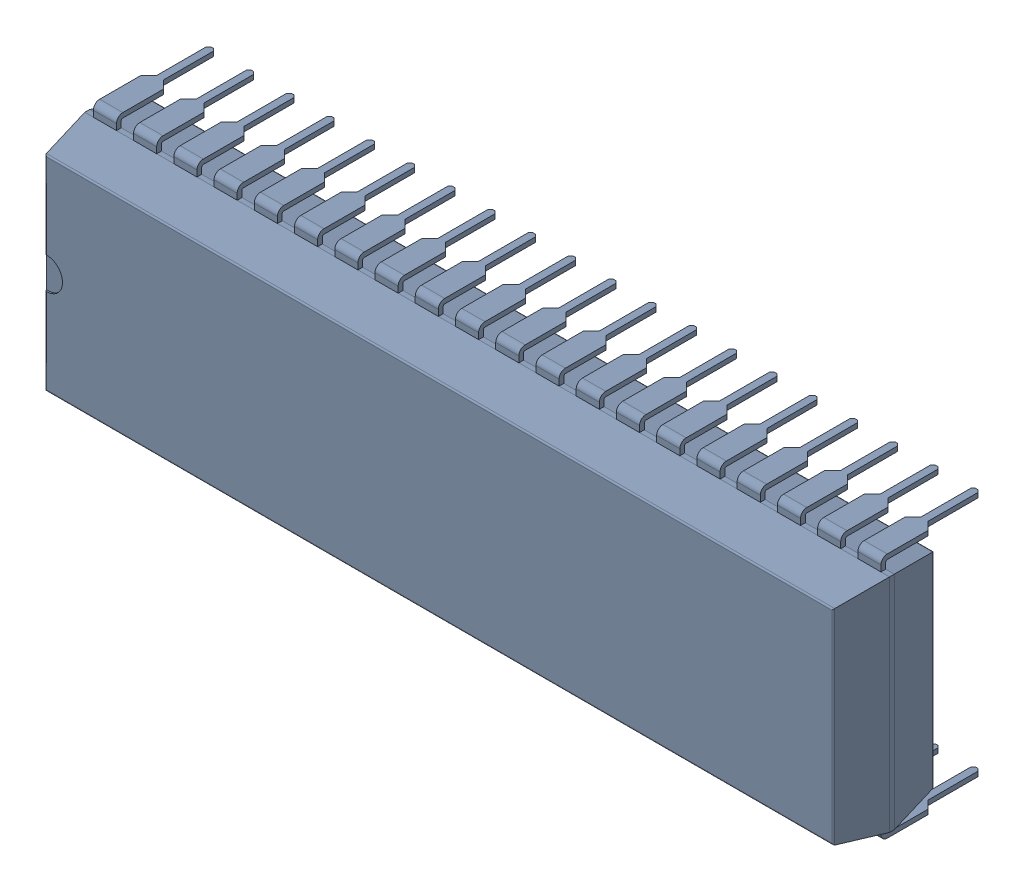
SolidWorks assembly U3, configuration Default. Lengths in mm.
Overall size (50.8 15.54 9.8).
2 component instances, 1 part files, 0 mates.
Components (placement in the parent):
- Open CASCADE STEP translator 6.8 1.1.1-1: Open CASCADE STEP translator 6.8 1.1.1 [Default] at origin size (50.8 15.54 9.8)
  - Body_1-1: Body_1 [Default] at (24 7.3 0) x (0 1 0) z (1 0 0) size (15.54 9.8 50.8)
